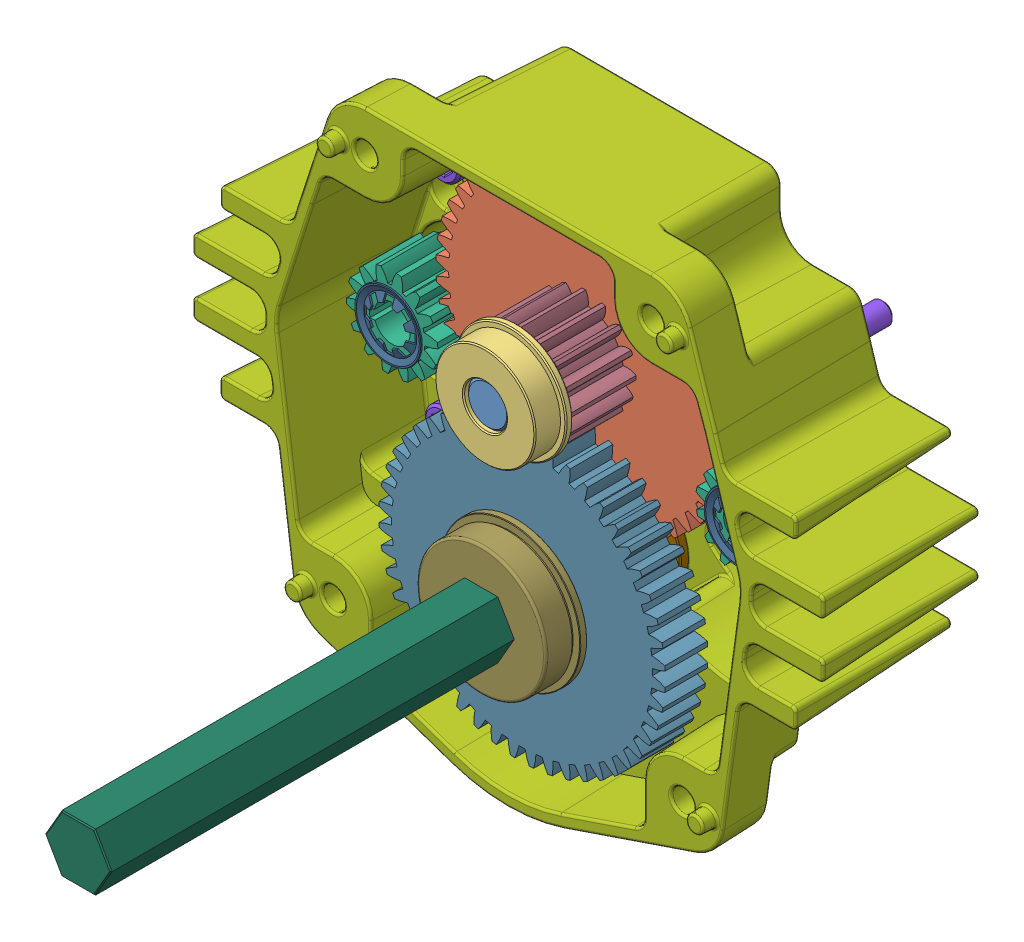
SolidWorks assembly am-2598_107 2016 KOP Toughbox Mini, configuration Default. Lengths in mm.
Overall size (140.05 121.81 142.29).
27 component instances, 15 part files, 0 mates.
Components (placement in the parent):
- Toughbox d07-1: Toughbox d07 [Default] at (-88.5589 93.4503 -52.3959) x (-0.336928 0.94153 0) z (0.94153 0.336928 0) size (11 38.23 9.52)
- Toughbox d05-1: Toughbox d05 [Default] at (-91.0349 50.9043 -67.5597) x (-0.336928 0.94153 0) z (0 0 -1) size (65.97 66.04 10.34)
- FR6ZZ Bearing-1: FR6ZZ Bearing [Default] at (-96.247 60.278 -52.5991) x (-0.893862 0.448342 0) z (0 0 1) size (24.69 24.69 7.16)
- 10-32 Nylock Nut-1: 10-32 Nylock Nut [Default] at (-129.8464 -8.0737 -56.3837) x (0.501678 0.865055 0) z (0 0 -1) size (9.53 11 5.96)
- 10-32 Nylock Nut-2: 10-32 Nylock Nut [Default] at (-59.2462 80.7349 -56.3837) x (0.999999 -0.001296 0) z (0 0 -1) size (9.53 11 5.96)
- 10-32 Nylock Nut-3: 10-32 Nylock Nut [Default] at (-122.7461 80.8172 -56.3837) x (0.500567 0.865698 0) z (0 0 -1) size (9.53 11 5.96)
- 10-32 Nylock Nut-4: 10-32 Nylock Nut [Default] at (-52.3764 -8.1741 -56.3837) x (-0.501678 -0.865055 0) z (0 0 -1) size (9.53 11 5.96)
- 5-16 washer-1: 5-16 washer [Default] at (-52.3162 38.3079 -77.7705) x (0.38418 -0.923258 0) z (0 0 -1) size (17.53 17.53 1.47)
- 5-16 washer-2: 5-16 washer [Default] at (-52.3162 38.3079 -76.2973) x (0.897267 -0.441488 0) z (0 0 -1) size (17.53 17.53 1.47)
- 5-16 washer-3: 5-16 washer [Default] at (-129.7861 38.4083 -77.7705) x (-0.990116 0.140253 0) z (0 0 1) size (17.53 17.53 1.47)
- 5-16 washer-4: 5-16 washer [Default] at (-129.7861 38.4083 -79.2437) x (-0.681761 0.731575 0) z (0 0 1) size (17.53 17.53 1.47)
- Toughbox d09-1: Toughbox d09 [Default] at (-52.3162 38.3079 -63.5973) x (0.910249 -0.414061 0) z (0 0 -1) size (20.03 20.32 12.7)
- Toughbox d09-2: Toughbox d09 [Default] at (-129.7861 38.4083 -63.5973) x (0.075368 -0.997156 0) z (0 0 -1) size (20.03 20.32 12.7)
- TM Housing-1: TM Housing [Default] at (-91.0876 10.1882 -86.3557) x (0.999999 -0.001296 0) z (0 0 1) size (139.9 118.55 41.62)
- SHCS 10-32 x 0.625-1: SHCS 10-32 x 0.625 [Default] at (-52.2832 63.7078 -74.4685) x (-0.564778 -0.825243 0) z (-0.825243 0.564778 0) size (7.82 20.65 7.82)
- SHCS 10-32 x 0.625-2: SHCS 10-32 x 0.625 [Default] at (-52.3491 12.9079 -74.4685) x (-0.564778 -0.825243 0) z (-0.825243 0.564778 0) size (7.82 20.65 7.82)
- SHCS 10-32 x 0.625-3: SHCS 10-32 x 0.625 [Default] at (-129.7532 63.8083 -74.4685) x (-0.966277 -0.257503 0) z (-0.257503 0.966277 0) size (7.82 20.65 7.82)
- SHCS 10-32 x 0.625-4: SHCS 10-32 x 0.625 [Default] at (-129.819 13.0083 -74.4685) x (-0.99652 0.083357 0) z (0.083357 0.99652 0) size (7.82 20.65 7.82)
- R6ZZ Bearing-1: R6ZZ Bearing [Default] at (-91.0349 50.9043 -84.8317) x (0.958138 -0.286306 0) z (0 0 1) size (22.23 22.23 7.11)
- R6ZZ Bearing-2: R6ZZ Bearing [Default] at (-91.0876 10.1882 -84.8317) x (-0.328282 -0.94458 0) z (0 0 1) size (22.23 22.23 7.11)
- 8mm spring clip-1: 8mm spring clip [Default] at (-129.7861 38.4083 -63.5973) x (0 0 1) z (-1 0 0) size (1.12 14.83 14.83)
- 8mm spring clip-2: 8mm spring clip [Default] at (-52.3162 38.3079 -63.5973) x (0 0 1) z (-1 0 0) size (1.12 14.83 14.83)
- 500 E-klip-1: 500 E-klip [Default] at (-91.0876 10.1882 -64.4355) x (0.996411 -0.084651 0) z (0 0 1) size (19.07 20.96 1.27)
- FR8ZZ Hex Bearing-1: FR8ZZ Hex Bearing [Default] at (-91.0876 10.1882 -44.6717) x (-0.5 0.866025 0) z (0 0 -1) size (31.12 31.12 7.93)
- 16t 20dp 375h with teeth-1: 16t 20dp 375h with teeth [Default] at (-91.0349 50.9043 -67.5597) x (0 0 1) z (-0.983853 0.178977 0) size (15.19 22.57 22.57)
- 48t 20dp 500h with teeth-1: 48t 20dp 500h with teeth [Default] at (-91.0876 10.1882 -63.1655) x (0 0 1) z (-1 0 0) size (10.21 63.42 63.42)
- TB Output Shaft Hex L-Base 2-1: TB Output Shaft Hex L-Base 2 [Default] at (-52.7805 -6.4809 -52.3197) x (1 0 0) z (0 -1 0) size (14.66 142.29 12.7)
